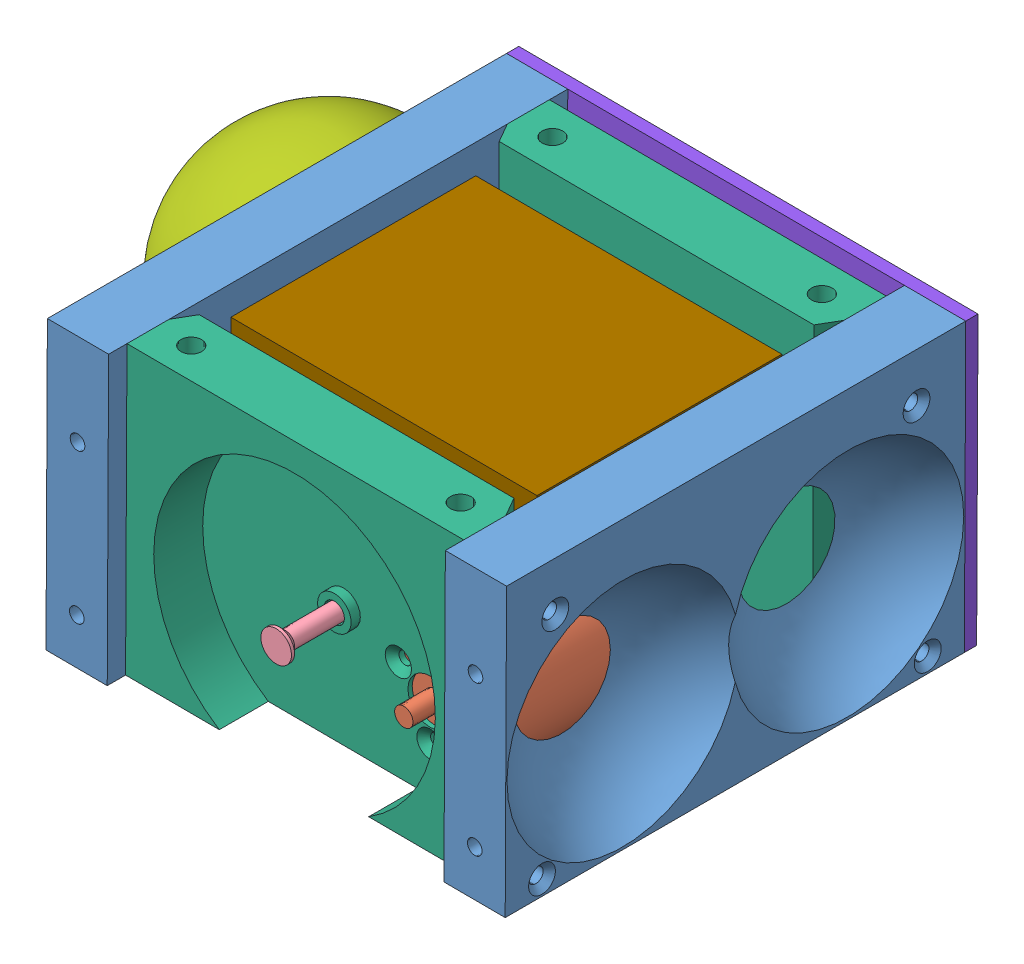
SolidWorks assembly miro2, configuration Default. Lengths in mm.
Overall size (114.72 51.45 83.86).
17 component instances, 10 part files, 37 mates.
Components (placement in the parent):
- 1 - Copy-1: 1 - Copy [Default] at (107.4225 -172.2581 96.2791) x (-0.999989 0.004779 0) z (0 0 -1) size (10 47 75)
- 1 - Copy-2: 1 - Copy [Default] at (107.4225 -172.2581 96.2791) x (0.999989 -0.004779 0) z (0 0 1) size (10 47 75)
- motor-1: motor [Default] at (93.3063 -158.8705 71.7791) x (0.687464 -0.726218 0) z (0 0 1) size (22 22 32.8)
- motor-2: motor [Default] at (121.666 -159.006 120.7791) x (-0.923728 -0.383049 0) z (0 0 -1) size (22 22 32.8)
- wheel-1: wheel [Default] at (107.5157 -152.7583 132.2791) x (-0.815887 0.578212 0) z (0 0 -1) size (43 43 8) (hidden)
- wheel-2: wheel [Default] at (107.5157 -152.7583 60.2791) x (0.09981 -0.995007 0) z (0 0 1) size (43 43 8)
- rod-1: rod [Default] at (107.5157 -152.7583 120.7791) x (-0.991364 -0.131136 0) z (0 0 1) size (5 5 13.42)
- rod-2: rod [Default] at (107.5157 -152.7583 71.7791) x (-0.415243 -0.90971 0) z (0 0 -1) size (5 5 13.42)
- bolt-1: bolt [Default] at (107.5157 -152.7583 71.7791) x (-0.423414 -0.905936 0) z (0 0 1) size (5.7 5.88 2)
- bolt-2: bolt [Default] at (107.5157 -152.7583 118.7791) x (0.915401 0.402543 0) z (0 0 1) size (5.7 5.88 2)
- circuit-1: circuit [Default] at (107.671 -120.2587 96.2791) x (0 0 1) z (-0.999989 0.004779 0) size (74 2 74) (hidden)
- new wheel cover-1: new wheel cover [Default] at (92.8077 -158.3135 71.7791) x (0 0 -1) z (0.999989 -0.004779 0) size (10 47 55)
- ball-1: ball [Default] at (60.1955 -152.6822 77.9291) x (0.097647 0.995174 -0.009657) z (0.374449 -0.027747 0.926832) size (42.7 42.7 42.7)
- new wheel cover-2: new wheel cover [Default] at (122.17 -158.4539 120.7791) x (0 0 1) z (-0.999989 0.004779 0) size (10 47 55)
- side support-1: side support [Default] at (107.5348 -148.7584 56.7791) x (0.999989 -0.004779 0) z (0 0 1) size (75 47 2)
- side support-2: side support [Default] at (107.5348 -148.7584 135.7791) x (-0.999989 0.004779 0) z (0 0 -1) size (75 47 2) (hidden)
- battery-1: battery [Default] at (82.1041 -147.8168 115.8639) x (0.004779 0.999989 0) z (0.999989 -0.004779 0) size (20 40 50)
Mates (geometry in assembly coordinates):
- Concentric6: concentric aligned: cylinder of rod-2 through (107.5157 -152.7583 58.7791) axis (0 0 1) radius 1.4; cylinder of wheel-2 through (107.5157 -152.7583 62.2791) axis (0 0 1) radius 18.65
- Concentric12: concentric anti-aligned: cylinder of wheel-1 through (107.5157 -152.7583 124.2791) axis (0 0 1) radius 21.5; cylinder of rod-1 through (107.5157 -152.7583 133.7791) axis (0 0 -1) radius 1.4
- Coincident71: coincident anti-aligned: plane of wheel-1 through (107.5157 -152.7583 132.2791) normal (0 0 1); plane of rod-1 through (107.5157 -152.7583 132.2791) normal (0 0 -1)
- Concentric13: concentric aligned: cylinder of rod-2 through (107.5157 -152.7583 60.2791) axis (0 0 -1) radius 2.5; cylinder of bolt-1 through (107.5157 -152.7583 73.7791) axis (0 0 -1) radius 1.5
- Concentric14: concentric anti-aligned: cylinder of rod-1 through (107.5157 -152.7583 132.2791) axis (0 0 1) radius 2.5; cylinder of bolt-2 through (107.5157 -152.7583 120.7791) axis (0 0 -1) radius 1.5
- Coincident78: coincident anti-aligned: plane of wheel-2 through (107.5157 -152.7583 60.2791) normal (0 0 -1); plane of rod-2 through (107.5157 -152.7583 60.2791) normal (0 0 1)
- Concentric20: concentric aligned: cylinder of wheel-2 through (107.5157 -152.7583 68.2791) axis (0 0 -1) radius 21.5; cylinder of new wheel cover-1 through (107.5157 -152.7583 69.7791) axis (0 0 -1) radius 23
- Coincident94: coincident aligned: plane of 1 - Copy-1 through (70.1475 -125.0794 58.7791) normal (0.004779 0.999989 0); plane of new wheel cover-1 through (135.1468 -125.39 61.7791) normal (0.004779 0.999989 0)
- Coincident95: coincident anti-aligned: plane of 1 - Copy-2 through (135.1468 -125.39 68.7791) normal (-0.999989 0.004779 0); plane of new wheel cover-1 through (135.1468 -125.39 61.7791) normal (0.999989 -0.004779 0)
- Concentric21: concentric anti-aligned: cylinder of motor-1 through (93.3063 -158.8705 95.7791) axis (0 0 -1) radius 11; cylinder of new wheel cover-1 through (93.3063 -158.8705 68.7791) axis (0 0 1) radius 3.635
- Coincident96: coincident anti-aligned: plane of motor-1 through (93.3063 -158.8705 71.7791) normal (0 0 -1); plane of new wheel cover-1 through (134.9222 -172.3895 71.7791) normal (0 0 1)
- Coincident97: coincident anti-aligned: plane of wheel-2 through (107.5157 -152.7583 68.2791) normal (0 0 1); plane of new wheel cover-1 through (107.5157 -152.7583 68.2791) normal (0 0 -1)
- Coincident98: coincident anti-aligned: plane of bolt-1 through (105.111 -150.9646 71.7791) normal (0 0 -1); plane of new wheel cover-1 through (134.9222 -172.3895 71.7791) normal (0 0 1)
- Coincident102: coincident aligned: plane of 1 - Copy-2 through (144.9221 -172.4373 133.7791) normal (-0.004779 -0.999989 0); plane of new wheel cover-1 through (134.9222 -172.3895 61.7791) normal (-0.004779 -0.999989 0)
- Coincident103: coincident anti-aligned: plane of 1 - Copy-1 through (80.1474 -125.1272 123.7791) normal (0.999989 -0.004779 0); plane of new wheel cover-1 through (80.1474 -125.1272 61.7791) normal (-0.999989 0.004779 0)
- Coincident116: coincident aligned: plane of 1 - Copy-1 through (70.1475 -125.0794 58.7791) normal (0.004779 0.999989 0); plane of new wheel cover-2 through (80.1474 -125.1272 130.7791) normal (0.004779 0.999989 0)
- Coincident117: coincident anti-aligned: plane of 1 - Copy-1 through (80.1474 -125.1272 123.7791) normal (0.999989 -0.004779 0); plane of new wheel cover-2 through (80.1474 -125.1272 130.7791) normal (-0.999989 0.004779 0)
- Concentric22: concentric anti-aligned: cylinder of motor-2 through (121.666 -159.006 96.7791) axis (0 0 1) radius 11; cylinder of new wheel cover-2 through (121.666 -159.006 123.7791) axis (0 0 -1) radius 3.635
- Coincident119: coincident anti-aligned: plane of motor-2 through (121.666 -159.006 120.7791) normal (0 0 1); plane of new wheel cover-2 through (79.9228 -172.1267 120.7791) normal (0 0 -1)
- Concentric23: concentric anti-aligned: cylinder of wheel-1 through (107.5157 -152.7583 124.2791) axis (0 0 1) radius 21.5; cylinder of new wheel cover-2 through (107.5157 -152.7583 124.2791) axis (0 0 -1) radius 2.75
- Coincident120: coincident anti-aligned: plane of wheel-1 through (107.5157 -152.7583 124.2791) normal (0 0 -1); plane of new wheel cover-2 through (107.5157 -152.7583 124.2791) normal (0 0 1)
- Coincident121: coincident anti-aligned: plane of bolt-2 through (108.1429 -155.692 120.7791) normal (0 0 1); plane of new wheel cover-2 through (79.9228 -172.1267 120.7791) normal (0 0 -1)
- Concentric24: concentric: sphere of 1 - Copy-1; sphere of ball-1
- Coincident122: coincident aligned: plane of 1 - Copy-1 through (145.1467 -125.4378 133.7791) normal (0 0 1); plane of rod-1 through (107.5157 -152.7583 133.7791) normal (0 0 1)
- Coincident124: coincident aligned: plane of 1 - Copy-2 through (70.1475 -125.0794 58.7791) normal (0 0 -1); plane of rod-2 through (107.5157 -152.7583 58.7791) normal (0 0 -1)
- Coincident125: coincident aligned: plane of 1 - Copy-1 through (145.1467 -125.4378 58.7791) normal (0 0 -1); plane of 1 - Copy-2 through (70.1475 -125.0794 58.7791) normal (0 0 -1)
- Coincident126: coincident anti-aligned: plane of 1 - Copy-2 through (70.1475 -125.0794 58.7791) normal (0 0 -1); plane of side support-1 through (144.9221 -172.4373 58.7791) normal (0 0 1)
- Coincident127: coincident aligned: plane of 1 - Copy-2 through (145.1467 -125.4378 133.7791) normal (0.004779 0.999989 0); plane of side support-1 through (70.1475 -125.0794 58.7791) normal (0.004779 0.999989 0)
- Coincident128: coincident aligned: plane of 1 - Copy-2 through (145.1467 -125.4378 58.7791) normal (0.999989 -0.004779 0); plane of side support-1 through (145.1467 -125.4378 58.7791) normal (0.999989 -0.004779 0)
- Coincident129: coincident anti-aligned: plane of 1 - Copy-1 through (145.1467 -125.4378 133.7791) normal (0 0 1); plane of side support-2 through (69.9229 -172.0789 133.7791) normal (0 0 -1)
- Coincident130: coincident aligned: plane of 1 - Copy-2 through (145.1467 -125.4378 133.7791) normal (0.004779 0.999989 0); plane of side support-2 through (145.1467 -125.4378 133.7791) normal (0.004779 0.999989 0)
- Coincident131: coincident aligned: plane of 1 - Copy-1 through (70.1475 -125.0794 133.7791) normal (-0.999989 0.004779 0); plane of side support-2 through (70.1475 -125.0794 133.7791) normal (-0.999989 0.004779 0)
- Tangent1: tangent anti-aligned: cylinder of motor-2 through (121.666 -159.006 96.7791) axis (0 0 1) radius 11; plane of battery-1 through (132.1035 -148.0558 115.8639) normal (-0.004779 -0.999989 0)
- Tangent2: tangent anti-aligned: cylinder of motor-1 through (93.3063 -158.8705 95.7791) axis (0 0 -1) radius 11; plane of battery-1 through (132.1035 -148.0558 115.8639) normal (-0.004779 -0.999989 0)
- Concentric25: concentric aligned: cylinder of circuit-1 through (85.6713 -120.1535 125.7791) axis (0.004779 0.999989 0) radius 1.7; cylinder of new wheel cover-2 through (85.6474 -125.1535 125.7791) axis (0.004779 0.999989 0) radius 1.7
- Distance1: distance = 5 mm anti-aligned: plane of new wheel cover-2 through (80.1474 -125.1272 130.7791) normal (0.004779 0.999989 0); plane of circuit-1 through (70.6714 -120.0819 133.2791) normal (-0.004779 -0.999989 0)
- Concentric26: concentric aligned: cylinder of circuit-1 through (129.6707 -120.3638 125.7791) axis (0.004779 0.999989 0) radius 1.7; cylinder of new wheel cover-2 through (129.6469 -125.3638 125.7791) axis (0.004779 0.999989 0) radius 1.7
